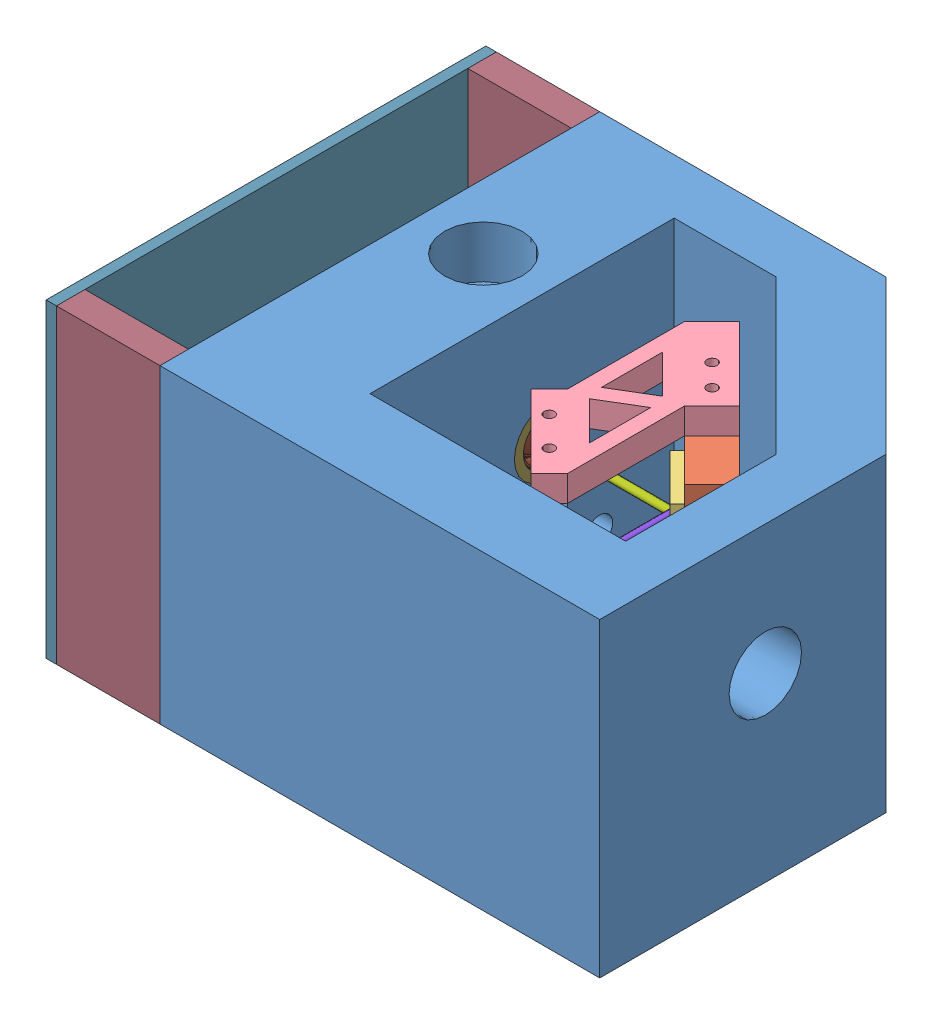
SolidWorks assembly Assem, configuration Default. Lengths in mm.
Overall size (107 63.3 85).
18 component instances, 16 part files, 27 mates.
Components (placement in the parent):
- box 1.5-1: box 1.5 [Default] at (2.7716 -27.6515 -2.0277) size (85 60 85)
- mirror mount part-2: mirror mount part [Default] at (10.6059 10.8584 -7.5009) x (-0.707107 0 -0.707107) z (0.707107 0 -0.707107) size (35 35 7.5)
- GR13-1208-Solidworks-1: GR13-1208-Solidworks [Default] at (8.1135 6.5625 -9.5563) x (-0.707107 0 -0.707107) z (0.707107 0 -0.707107) size (12.7 12.7 6)
- arm-2: arm [Default] at (15.2233 23.1309 4.896) x (0.707107 0 0.707107) z (-0.707107 0 0.707107) size (36 30.8 28.5)
  - arm part1-1: arm part1 [Default] at (11.3756 1.7176 21.9737) size (36 5 28.5)
  - arm part2-1: arm part2 [Default] at (14.2887 -30.1155 10.4991) size (20 25 5)
  - BB05-E03-Solidworks-1: BB05-E03-Solidworks [Default] at (-48.8905 -39.0424 39.3094) x (-0.923728 -0.383049 0) z (0 0 -1) size (12.7 12.7 6)
- laser1-1: laser1 [Default] at (-14.9342 -16.235 -15.6441) x (1 0 0) z (0 0.683204 0.730227) size (26 1.5 1.5)
- laser2-1: laser2 [Default] at (17.2295 31.3324 12.6197) x (0 0 -1) z (-0.697057 -0.717016 0) size (20 1.5 1.5)
- laser3-1: laser3 [Default] at (4.1834 -2.871 -11.1849) x (0.9999 -0.014153 0) z (-0.000477 -0.033712 0.999431) size (30 1.5 1.5)
- colimation tube assembly final-1: colimation tube assembly final [Default] at (6.4841 5.354 -23.5122) x (1 0 0) z (0 0.034606 0.999401) size (29 13 13)
  - diode-1: diode [Default] at (-37.8768 1.4091 16.9409) x (0 0 1) z (-1 0 0) size (9 9 14.45)
  - C220TME-B-Solidworks-1: C220TME-B-Solidworks [Default] at (-29.1282 1.4091 16.9409) x (0 -0.977212 0.212268) z (0 0.212268 0.977212) size (9.24 7.19 9.24)
  - colimation tube final ver2-1: colimation tube final ver2 [Default] at (-46.4182 1.4091 22.5957) x (0 0 -1) z (1 0 0) size (13 13 25)
- back-1: back [Default] at (-39.9342 18.5203 16.5104) x (0 0 1) z (-1 0 0) size (85 60 20)
- plate-2: plate [Default] at (-61.9342 9.8489 -14.3231) x (0 0 -1) z (1 0 0) size (85 60 2)
- TEC-1: TEC [Default] at (13.9994 -30.9515 3.0637) size (62 3.3 62)
- bottom-2: bottom [Default] at (1.226 -35.9515 -21.8342) size (85 5 85) (hidden)
Mates (geometry in assembly coordinates):
- Distance1: distance = 5 mm anti-aligned: plane of mirror mount part-2 through (15.9092 10.8584 -12.8042) normal (0.707107 0 -0.707107); plane of box 1.5-1 through (4.7641 32.3485 -31.0203) normal (-0.707107 0 0.707107)
- Coincident28: coincident anti-aligned: plane of mirror mount part-2 through (13.4343 10.8584 -10.3293) normal (-0.707107 0 0.707107); plane of GR13-1208-Solidworks-1 through (17.9836 0.8485 -5.78) normal (0.707107 0 -0.707107)
- Coincident36: coincident anti-aligned: line of mirror mount part-2 through (9.0034 13.8485 -14.7602) axis (0 -1 0); line of GR13-1208-Solidworks-1 through (9.0034 0.8485 -14.7602) axis (0 1 0)
- Coincident38: coincident anti-aligned: line of mirror mount part-2 through (9.0034 0.8485 -14.7602) axis (0.707107 0 0.707107); line of GR13-1208-Solidworks-1 through (17.9836 0.8485 -5.78) axis (-0.707107 0 -0.707107)
- Coincident51: coincident anti-aligned: plane of mirror mount part-2 through (28.4488 24.8485 -0.2645) normal (0 1 0); plane of arm-2/arm part1-1 through (7.7293 24.8485 28.4775) normal (0 -1 0)
- Coincident52: coincident aligned: plane of mirror mount part-2 through (15.9092 10.8584 -12.8042) normal (0.707107 0 -0.707107); plane of arm-2/arm part1-1 through (32.4601 24.8485 3.7467) normal (0.707107 0 -0.707107)
- Parallel1: parallel anti-aligned: plane of box 1.5-1 through (-14.9342 32.3485 27.7597) normal (0 0 -1); plane of laser2-1 through (9.3425 7.3485 12.6197) normal (0 0 1)
- Concentric7: concentric aligned: circle of box 1.5-1; circle of mirror mount part-2
- Concentric8: concentric aligned: circle of mirror mount part-2; circle of arm-2/arm part1-1
- Concentric9: concentric aligned: circle of box 1.5-1; circle of mirror mount part-2
- Concentric10: concentric anti-aligned: circle of laser1-1; circle of colimation tube assembly final-1/C220TME-B-Solidworks-1
- Tangent4: tangent aligned: cylinder of laser1-1 through (11.0658 7.3485 -6.6303) axis (-1 0 0) radius 0.75; cylinder of laser2-1 through (9.3425 7.3485 -7.3803) axis (0 0 1) radius 0.75
- Tangent5: tangent aligned: cylinder of laser2-1 through (9.3425 7.3485 -7.3803) axis (0 0 1) radius 0.75; cylinder of laser3-1 through (34.3261 6.9949 11.8697) axis (-0.9999 0.014153 0) radius 0.75
- Tangent6: tangent aligned: cylinder of laser1-1 through (11.0658 7.3485 -6.6303) axis (-1 0 0) radius 0.75; plane of laser2-1 through (9.3425 7.3485 -7.3803) normal (0 0 -1)
- Tangent7: tangent aligned: plane of laser2-1 through (9.3425 7.3485 12.6197) normal (0 0 1); cylinder of laser3-1 through (34.3261 6.9949 11.8697) axis (-0.9999 0.014153 0) radius 0.75
- Coincident62: coincident anti-aligned: plane of box 1.5-1 through (-39.9342 32.3485 -41.6303) normal (-1 0 0); plane of back-1 through (-39.9342 18.5203 16.5104) normal (1 0 0)
- Concentric11: concentric aligned: circle of box 1.5-1; circle of back-1
- Coincident65: coincident aligned: plane of box 1.5-1 through (-14.9342 32.3485 -31.0203) normal (1 0 0); plane of colimation tube assembly final-1/colimation tube final ver2-1 through (-14.9342 7.3485 -6.6303) normal (1 0 0)
- Coincident66: coincident anti-aligned: circle of box 1.5-1; circle of colimation tube assembly final-1/colimation tube final ver2-1
- Concentric19: concentric aligned: circle of box 1.5-1; circle of back-1
- Coincident72: coincident anti-aligned: plane of back-1 through (-59.9342 18.5203 16.5104) normal (-1 0 0); plane of plate-2 through (-59.9342 9.8489 -14.3231) normal (1 0 0)
- Concentric20: concentric anti-aligned: circle of back-1; circle of plate-2
- Concentric21: concentric aligned: circle of back-1; circle of plate-2
- Coincident73: coincident anti-aligned: plane of box 1.5-1 through (2.7716 -27.6515 -2.0277) normal (0 -1 0); plane of TEC-1 through (17.9286 -27.6515 4.4403) normal (0 1 0)
- Coincident75: coincident anti-aligned: plane of TEC-1 through (17.9286 -30.9515 4.4403) normal (0 -1 0); plane of bottom-2 through (1.226 -30.9515 -21.8342) normal (0 1 0)
- Concentric22: concentric aligned: circle of box 1.5-1; circle of bottom-2
- Concentric23: concentric aligned: circle of box 1.5-1; circle of bottom-2
